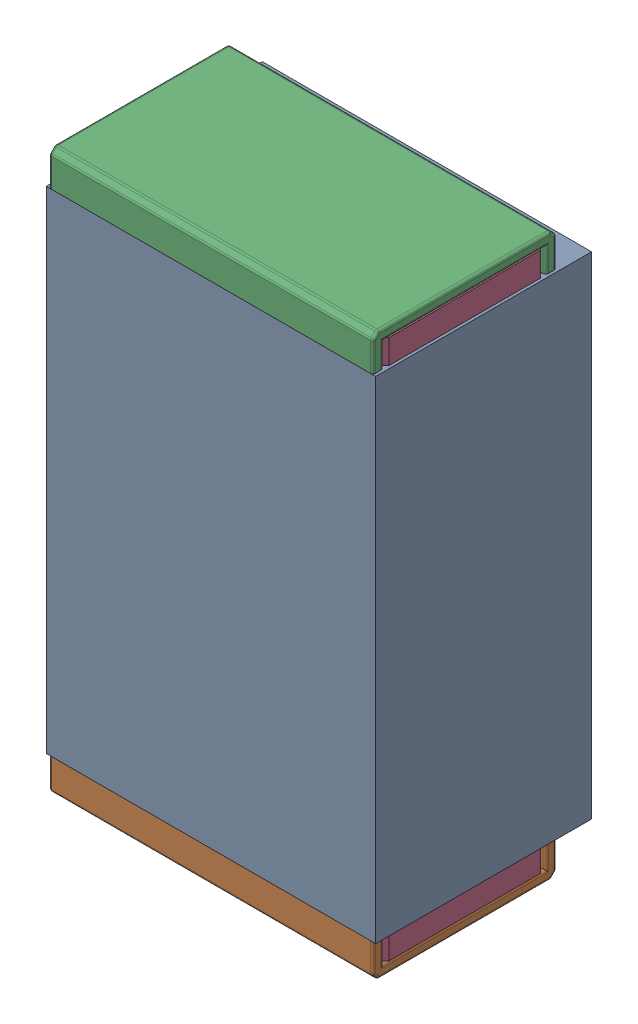
SolidWorks assembly R24, configuration Default. Lengths in mm.
Overall size (0.61 1.04 0.4).
3 component instances, 2 part files, 0 mates.
Components (placement in the parent):
- 1088881848-1: 1088881848 [Default] at (2.475 2.8 -2.044) size (0.61 0.91 0.4)
  - Extruded-1-1: Extruded-1 [Default] at origin size (0.61 0.91 0.4)
- R0402-1: R0402 [Default] at (2.475 2.8 -1.644) x (0 -1 0) z (1 0 0) size (1.04 0.34 0.6)
